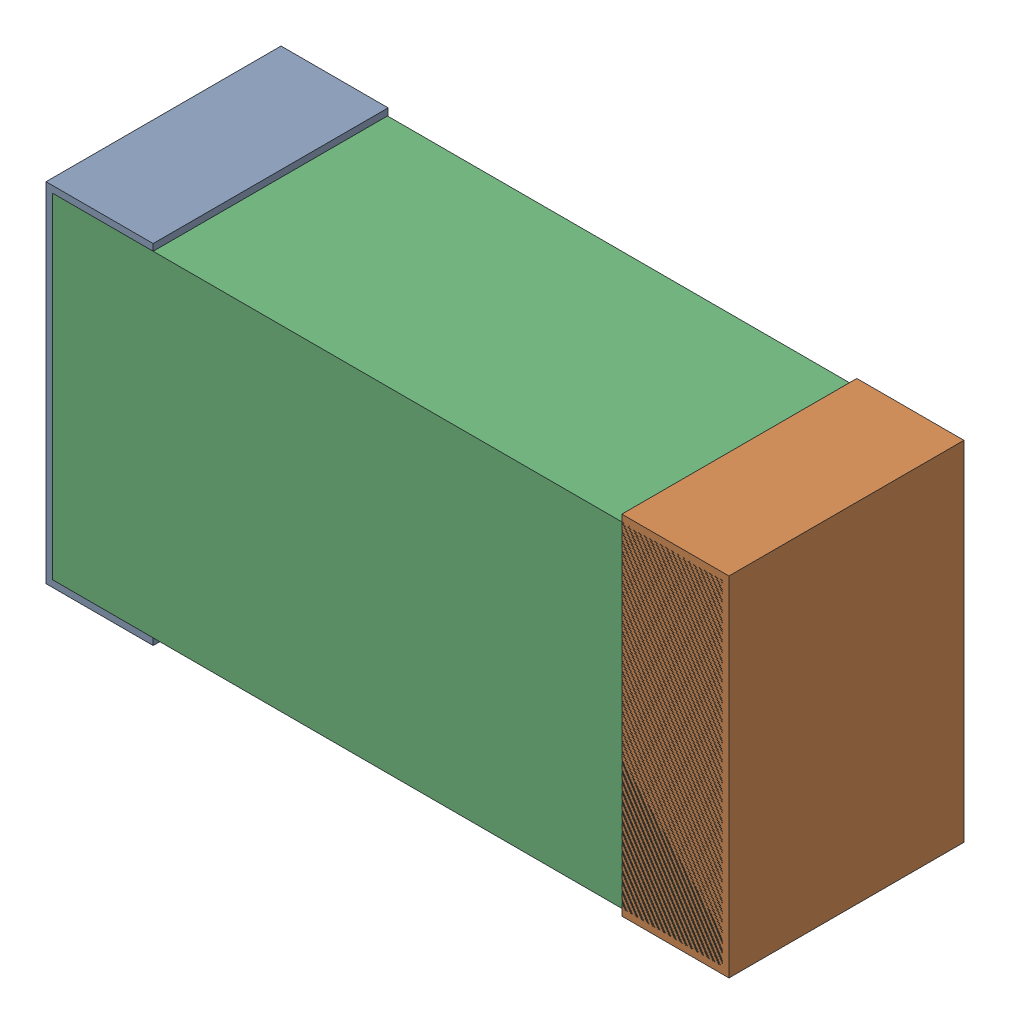
SolidWorks assembly C29, configuration Default. Lengths in mm.
Overall size (1.02 0.52 0.35).
6 component instances, 2 part files, 0 mates.
Components (placement in the parent):
- 870940480-1: 870940480 [Default] at (25.528 26.617 -1.9516) size (0.16 0.52 0.35)
  - Extruded-1: Extruded [Default] at origin size (0.16 0.52 0.35)
- 870940480-2: 870940480 [Default] at (26.388 26.617 -1.9516) size (0.16 0.52 0.35)
  - Extruded-1: Extruded [Default] at origin size (0.16 0.52 0.35)
- 870940640-1: 870940640 [Default] at (25.958 26.617 -1.9506) size (1 0.5 0.35)
  - Extruded_2-1: Extruded_2 [Default] at origin size (1 0.5 0.35)
